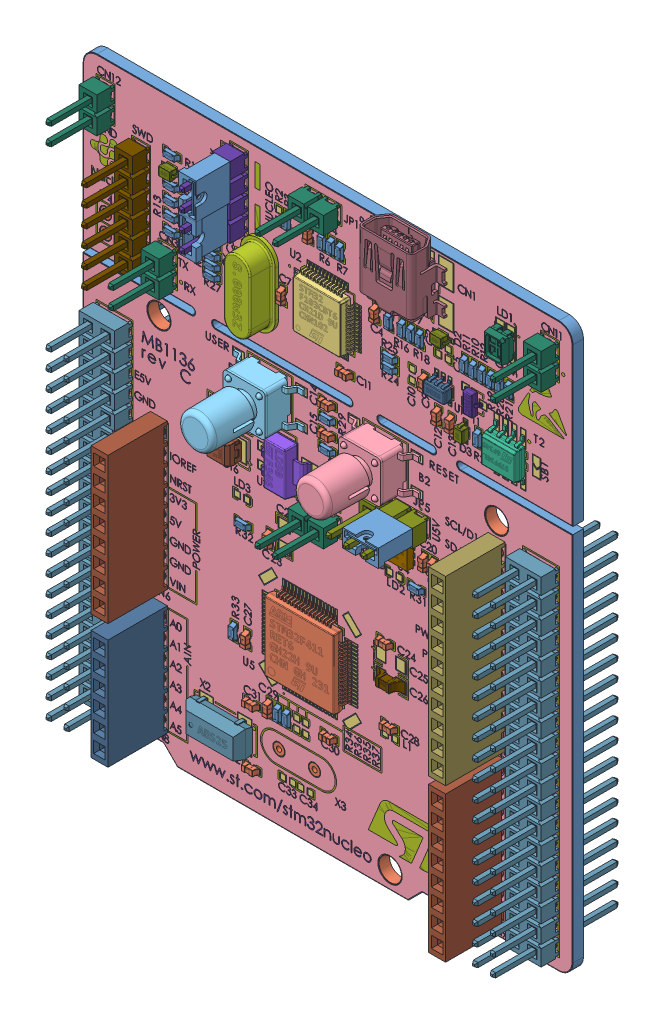
SolidWorks assembly NUCLEO-F4, configuration По умолчанию. Lengths in mm.
Overall size (70 83.97 20.27).
102 component instances, 38 part files, 0 mates.
Components (placement in the parent):
- NUCLEO-F411RE_PCB_VarsayВЌlan-1: NUCLEO-F411RE_PCB_VarsayВЌlan [По умолчанию] at origin size (70 82.5 1.5)
- NUCLEO-F411RE_PCB_HOLEs_VarsayВЌlan-1: NUCLEO-F411RE_PCB_HOLEs_VarsayВЌlan [По умолчанию] at origin size (65.28 79.87 1.57)
- NUCLEO-F411RE_PCB_TOP_Pads_VarsayВЌlan-1: NUCLEO-F411RE_PCB_TOP_Pads_VarsayВЌlan [По умолчанию] at origin size (59.94 77.1 0.04)
- NUCLEO-F411RE_PCB_TOP_Solder_VarsayВЌlan-1: NUCLEO-F411RE_PCB_TOP_Solder_VarsayВЌlan [По умолчанию] at origin size (69.8 82.3 0.05)
- NUCLEO-F411RE_PCB_BOTTOM_Pads_VarsayВЌlan-1: NUCLEO-F411RE_PCB_BOTTOM_Pads_VarsayВЌlan [По умолчанию] at origin size (31.1 70.87 0.04)
- NUCLEO-F411RE_PCB_BOTTOM_Solder_VarsayВЌlan-1: NUCLEO-F411RE_PCB_BOTTOM_Solder_VarsayВЌlan [По умолчанию] at origin size (69.8 82.3 0.04)
- NUCLEO-F411RE_PCB_TOP_Overlay_VarsayВЌlan-1: NUCLEO-F411RE_PCB_TOP_Overlay_VarsayВЌlan [По умолчанию] at origin size (68.11 77.69 0.03)
- NUCLEO-F411RE_PCB_TOP_Designators_VarsayВЌlan-1: NUCLEO-F411RE_PCB_TOP_Designators_VarsayВЌlan [По умолчанию] at origin size (66.31 79.66 0.03)
- NUCLEO-F411RE_PCB_BOTTOM_Overlay_VarsayВЌlan-1: NUCLEO-F411RE_PCB_BOTTOM_Overlay_VarsayВЌlan [По умолчанию] at origin size (40.14 80.79 0.03)
- SAMTEC_SSQ-106-01-G-S_for_NUCLEO_VarsayВЌlan-1: SAMTEC_SSQ-106-01-G-S_for_NUCLEO_VarsayВЌlan [По умолчанию] at (-33.02 8.89 0.785) x (0 1 0) z (1 0 0) size (15.75 11.15 2.41)
- SAMTEC_SSQ-108-01-G-S_for_NUCLEO_VarsayВЌlan-1: SAMTEC_SSQ-108-01-G-S_for_NUCLEO_VarsayВЌlan [По умолчанию] at (-33.02 29.21 0.785) x (0 1 0) z (1 0 0) size (20.83 11.15 2.41)
- SAMTEC_SSQ-110-01-G-S_for_NUCLEO_VarsayВЌlan-1: SAMTEC_SSQ-110-01-G-S_for_NUCLEO_VarsayВЌlan [По умолчанию] at (15.24 35.814 0.785) x (0 1 0) z (1 0 0) size (25.91 11.15 2.41)
- MOLEX_0678038020_for_NUCLEO-1: MOLEX_0678038020_for_NUCLEO [По умолчанию] at (3.1721 75.2975 0.785) x (-1 0 0) z (0 1 0) size (9.9 4.95 9)
- SAMTEC_TSW-119-07-T-D_for_NUCLEO_VarsayВЌlan-1: SAMTEC_TSW-119-07-T-D_for_NUCLEO_VarsayВЌlan [По умолчанию] at (-39.37 25.4 0.785) x (0 -1 0) z (-1 0 0) size (48.26 17.95 5.08)
- SAMTEC_TSW-102-07-T-S_for_NUCLEO_VarsayВЌlan-1: SAMTEC_TSW-102-07-T-S_for_NUCLEO_VarsayВЌlan [По умолчанию] at (-40.64 74.93 0.785) x (0 1 0) z (1 0 0) size (5.08 10.92 2.54)
- SAMTEC_TSW-103-07-T-S_for_NUCLEO_VarsayВЌlan-1: SAMTEC_TSW-103-07-T-S_for_NUCLEO_VarsayВЌlan [По умолчанию] at (1.905 45.085 0.785) x (1 0 0) z (0 -1 0) size (7.62 10.92 2.54)
- SAMTEC_TSW-104-07-T-S_for_NUCLEO_VarsayВЌlan-1: SAMTEC_TSW-104-07-T-S_for_NUCLEO_VarsayВЌlan [По умолчанию] at (-21.59 73.66 0.785) x (0 1 0) z (1 0 0) size (10.16 10.92 2.54)
- SAMTEC_TSW-106-07-T-S_for_NUCLEO_VarsayВЌlan-1: SAMTEC_TSW-106-07-T-S_for_NUCLEO_VarsayВЌlan [По умолчанию] at (-35.56 64.77 0.785) x (0 1 0) z (1 0 0) size (15.24 10.92 2.54)
- MOLEX_90059-0007-1: MOLEX_90059-0007 [По умолчанию] at (-21.59 76.2 5.75) x (0 1 0) z (1 0 0) size (5.1 4.85 2.54)
- ST_STM32F411RET6_VarsayВЌlan-1: ST_STM32F411RET6_VarsayВЌlan [По умолчанию] at (-11.4265 21.5935 0.785) x (-1 0 0) z (0 0 -1) size (12 12 1.61)
- ST_STM32F103CBT6_VarsayВЌlan-1: ST_STM32F103CBT6_VarsayВЌlan [По умолчанию] at (-8.89 64.77 0.785) x (1 0 0) z (0 -1 0) size (9 1.61 9)
- ESWITCH_TL3301SPF160QGBLK_VarsayВЌlan-1: ESWITCH_TL3301SPF160QGBLK_VarsayВЌlan [По умолчанию] at (-0.635 50.8 0.785) x (0 -1 0) z (-1 0 0) size (6.01 10.7 10)
- ESWITCH_TL3301SPF160QGBLU_VarsayВЌlan-1: ESWITCH_TL3301SPF160QGBLU_VarsayВЌlan [По умолчанию] at (-17.145 50.8 0.785) x (0 1 0) z (1 0 0) size (6.01 10.7 10)
- ST_STS7PF30L_VarsayВЌlan-1: ST_STS7PF30L_VarsayВЌlan [По умолчанию] at (17.145 60.325 0.785) x (-1 0 0) z (0 1 0) size (4.91 1.76 6)
- ABRACON_ABL-8-1: ABRACON_ABL-8 [По умолчанию] at (-18.41 63.4908 0.785) x (0 -1 0) z (-1 0 0) size (11.5 5.59 5)
- ST_LD1117S50TR_VarsayВЌlan-1: ST_LD1117S50TR_VarsayВЌlan [По умолчанию] at (-14.6685 43.18 0.785) x (0 -1 0) z (-1 0 0) size (6.51 1.91 7)
- ST_LD39050PU33R_VarsayВЌlan-1: ST_LD39050PU33R_VarsayВЌlan [По умолчанию] at (1.905 40.64 0.785) x (0 1 0) z (1 0 0) size (3.01 1.01 3.01)
- ST_LD3985M33R_VarsayВЌlan-1: ST_LD3985M33R_VarsayВЌlan [По умолчанию] at (7.62 63.5 0.785) x (1 0 0) z (0 -1 0) size (2.96 1.46 2.8)
- KEMET_T491B106K025AT_VarsayВЌlan-1: KEMET_T491B106K025AT_VarsayВЌlan [По умолчанию] at (-22.86 41.275 0.785) x (0 -1 0) z (-1 0 0) size (2.81 1.91 3.5)
- ST_STPS2L30A_VarsayВЌlan-1: ST_STPS2L30A_VarsayВЌlan [По умолчанию] at (-22.86 45.085 0.785) x (0 1 0) z (1 0 0) size (2.59 2.31 5.07)
- KEMET_T491A106K006AT7280_VarsayВЌlan-1: KEMET_T491A106K006AT7280_VarsayВЌlan [По умолчанию] at (-8.255 43.053 0.785) x (1 0 0) z (0 -1 0) size (1.61 1.61 3.2)
- ABRACON_ABS25-32-1: ABRACON_ABS25-32 [По умолчанию] at (-23.495 6.35 0.785) x (1 0 0) z (0 -1 0) size (8 2.67 4)
- LUMEX_SML-LX2835IGC-TR-1: LUMEX_SML-LX2835IGC-TR [По умолчанию] at (16.51 73.66 0.785) x (1 0 0) z (0 -1 0) size (2.7 1.8 3.5)
- ST_BAT60JFILM_VarsayВЌlan-1: ST_BAT60JFILM_VarsayВЌlan [По умолчанию] at (-31.115 71.12 0.785) x (0 -1 0) z (-1 0 0) size (1.29 1.18 2.5)
- NXP_BC847B,215-1: NXP_BC847B,215 [По умолчанию] at (12.065 64.135 0.785) x (0 -1 0) z (-1 0 0) size (2.9 1.11 2.43)
- YAGEO_CC0805KKX7R7BB225-1: YAGEO_CC0805KKX7R7BB225 [По умолчанию] at (0.127 23.495 0.785) x (0 -1 0) z (-1 0 0) size (1.59 1.29 4.06)
- YAGEO_RC0603JR-070RL-1: YAGEO_RC0603JR-070RL [По умолчанию] at (17.145 67.945 0.785) x (1 0 0) z (0 -1 0) size (0.8 0.55 2.16)
- YAGEO_CC0603KRX7R7BB104-1: YAGEO_CC0603KRX7R7BB104 [По умолчанию] at (-11.43 73.025 0.785) x (1 0 0) z (0 -1 0) size (0.8 0.8 2.16)
- SAMTEC_SSQ-108-01-G-S_for_NUCLEO_VarsayВЌlan-2: SAMTEC_SSQ-108-01-G-S_for_NUCLEO_VarsayВЌlan [По умолчанию] at (15.24 11.43 0.785) x (0 1 0) z (1 0 0) size (20.83 11.15 2.41)
- SAMTEC_TSW-119-07-T-D_for_NUCLEO_VarsayВЌlan-2: SAMTEC_TSW-119-07-T-D_for_NUCLEO_VarsayВЌlan [По умолчанию] at (21.59 25.4 0.785) x (0 -1 0) z (-1 0 0) size (48.26 17.95 5.08)
- SAMTEC_TSW-102-07-T-S_for_NUCLEO_VarsayВЌlan-2: SAMTEC_TSW-102-07-T-S_for_NUCLEO_VarsayВЌlan [По умолчанию] at (-31.75 59.055 0.785) x (0 -1 0) z (-1 0 0) size (5.08 10.92 2.54)
- SAMTEC_TSW-102-07-T-S_for_NUCLEO_VarsayВЌlan-3: SAMTEC_TSW-102-07-T-S_for_NUCLEO_VarsayВЌlan [По умолчанию] at (-9.525 77.47 0.785) x (1 0 0) z (0 -1 0) size (5.08 10.92 2.54)
- SAMTEC_TSW-102-07-T-S_for_NUCLEO_VarsayВЌlan-4: SAMTEC_TSW-102-07-T-S_for_NUCLEO_VarsayВЌlan [По умолчанию] at (-9.525 38.735 0.785) x (1 0 0) z (0 -1 0) size (5.08 10.92 2.54)
- SAMTEC_TSW-102-07-T-S_for_NUCLEO_VarsayВЌlan-5: SAMTEC_TSW-102-07-T-S_for_NUCLEO_VarsayВЌlan [По умолчанию] at (22.86 74.93 0.785) x (0 -1 0) z (-1 0 0) size (5.08 10.92 2.54)
- MOLEX_90059-0007-2: MOLEX_90059-0007 [По умолчанию] at (-21.59 71.12 5.75) x (0 -1 0) z (-1 0 0) size (5.1 4.85 2.54)
- MOLEX_90059-0007-3: MOLEX_90059-0007 [По умолчанию] at (3.175 45.085 5.75) x (-1 0 0) z (0 1 0) size (5.1 4.85 2.54)
- ST_BAT60JFILM_VarsayВЌlan-2: ST_BAT60JFILM_VarsayВЌlan [По умолчанию] at (7.62 69.85 0.785) x (0 -1 0) z (-1 0 0) size (1.29 1.18 2.5)
- ST_BAT60JFILM_VarsayВЌlan-3: ST_BAT60JFILM_VarsayВЌlan [По умолчанию] at (10.795 59.69 0.785) x (1 0 0) z (0 -1 0) size (1.29 1.18 2.5)
- YAGEO_RC0603JR-070RL-2: YAGEO_RC0603JR-070RL [По умолчанию] at (15.875 67.945 0.785) x (1 0 0) z (0 -1 0) size (0.8 0.55 2.16)
- YAGEO_RC0603JR-070RL-3: YAGEO_RC0603JR-070RL [По умолчанию] at (14.605 67.945 0.785) x (1 0 0) z (0 -1 0) size (0.8 0.55 2.16)
- YAGEO_RC0603JR-070RL-4: YAGEO_RC0603JR-070RL [По умолчанию] at (13.335 67.945 0.785) x (1 0 0) z (0 -1 0) size (0.8 0.55 2.16)
- YAGEO_RC0603JR-070RL-5: YAGEO_RC0603JR-070RL [По умолчанию] at (12.065 67.945 0.785) x (1 0 0) z (0 -1 0) size (0.8 0.55 2.16)
- YAGEO_RC0603JR-070RL-6: YAGEO_RC0603JR-070RL [По умолчанию] at (10.795 67.945 0.785) x (1 0 0) z (0 -1 0) size (0.8 0.55 2.16)
- YAGEO_RC0603JR-070RL-7: YAGEO_RC0603JR-070RL [По умолчанию] at (12.7 59.7535 0.785) x (1 0 0) z (0 -1 0) size (0.8 0.55 2.16)
- YAGEO_RC0603JR-070RL-8: YAGEO_RC0603JR-070RL [По умолчанию] at (4.445 67.945 0.785) x (1 0 0) z (0 -1 0) size (0.8 0.55 2.16)
- YAGEO_RC0603JR-070RL-9: YAGEO_RC0603JR-070RL [По умолчанию] at (3.175 67.945 0.785) x (1 0 0) z (0 -1 0) size (0.8 0.55 2.16)
- YAGEO_RC0603JR-070RL-10: YAGEO_RC0603JR-070RL [По умолчанию] at (1.905 67.945 0.785) x (1 0 0) z (0 -1 0) size (0.8 0.55 2.16)
- YAGEO_RC0603JR-070RL-11: YAGEO_RC0603JR-070RL [По умолчанию] at (0 67.945 0.785) x (1 0 0) z (0 -1 0) size (0.8 0.55 2.16)
- YAGEO_RC0603JR-070RL-12: YAGEO_RC0603JR-070RL [По умолчанию] at (-6.985 73.025 0.785) x (1 0 0) z (0 -1 0) size (0.8 0.55 2.16)
- YAGEO_RC0603JR-070RL-13: YAGEO_RC0603JR-070RL [По умолчанию] at (-8.255 73.025 0.785) x (1 0 0) z (0 -1 0) size (0.8 0.55 2.16)
- YAGEO_RC0603JR-070RL-14: YAGEO_RC0603JR-070RL [По умолчанию] at (-9.525 73.025 0.785) x (1 0 0) z (0 -1 0) size (0.8 0.55 2.16)
- YAGEO_RC0603JR-070RL-15: YAGEO_RC0603JR-070RL [По умолчанию] at (-14.605 73.025 0.785) x (1 0 0) z (0 -1 0) size (0.8 0.55 2.16)
- YAGEO_RC0603JR-070RL-16: YAGEO_RC0603JR-070RL [По умолчанию] at (-31.115 73.025 0.785) x (0 -1 0) z (-1 0 0) size (0.8 0.55 2.16)
- YAGEO_RC0603JR-070RL-17: YAGEO_RC0603JR-070RL [По умолчанию] at (-31.115 69.215 0.785) x (0 -1 0) z (-1 0 0) size (0.8 0.55 2.16)
- YAGEO_RC0603JR-070RL-18: YAGEO_RC0603JR-070RL [По умолчанию] at (-31.115 67.31 0.785) x (0 -1 0) z (-1 0 0) size (0.8 0.55 2.16)
- YAGEO_RC0603JR-070RL-19: YAGEO_RC0603JR-070RL [По умолчанию] at (-31.115 65.405 0.785) x (0 -1 0) z (-1 0 0) size (0.8 0.55 2.16)
- YAGEO_RC0603JR-070RL-20: YAGEO_RC0603JR-070RL [По умолчанию] at (-31.115 63.5 0.785) x (0 -1 0) z (-1 0 0) size (0.8 0.55 2.16)
- YAGEO_RC0603JR-070RL-21: YAGEO_RC0603JR-070RL [По умолчанию] at (-25.4 64.77 0.785) x (0 -1 0) z (-1 0 0) size (0.8 0.55 2.16)
- YAGEO_RC0603JR-070RL-22: YAGEO_RC0603JR-070RL [По умолчанию] at (-25.4 63.5 0.785) x (0 -1 0) z (-1 0 0) size (0.8 0.55 2.16)
- YAGEO_RC0603JR-070RL-23: YAGEO_RC0603JR-070RL [По умолчанию] at (-25.4 62.23 0.785) x (0 -1 0) z (-1 0 0) size (0.8 0.55 2.16)
- YAGEO_RC0603JR-070RL-24: YAGEO_RC0603JR-070RL [По умолчанию] at (-25.4 60.96 0.785) x (0 -1 0) z (-1 0 0) size (0.8 0.55 2.16)
- YAGEO_RC0603JR-070RL-25: YAGEO_RC0603JR-070RL [По умолчанию] at (-15.875 11.43 0.785) x (1 0 0) z (0 -1 0) size (0.8 0.55 2.16)
- YAGEO_RC0603JR-070RL-26: YAGEO_RC0603JR-070RL [По умолчанию] at (-14.605 11.43 0.785) x (1 0 0) z (0 -1 0) size (0.8 0.55 2.16)
- YAGEO_RC0603JR-070RL-27: YAGEO_RC0603JR-070RL [По умолчанию] at (-22.225 18.415 0.785) x (1 0 0) z (0 -1 0) size (0.8 0.55 2.16)
- YAGEO_RC0603JR-070RL-28: YAGEO_RC0603JR-070RL [По умолчанию] at (-20.955 32.385 0.785) x (0 -1 0) z (-1 0 0) size (0.8 0.55 2.16)
- YAGEO_RC0603JR-070RL-29: YAGEO_RC0603JR-070RL [По умолчанию] at (-8.89 51.435 0.785) x (0 -1 0) z (-1 0 0) size (0.8 0.55 2.16)
- YAGEO_RC0603JR-070RL-30: YAGEO_RC0603JR-070RL [По умолчанию] at (-8.89 47.625 0.785) x (0 -1 0) z (-1 0 0) size (0.8 0.55 2.16)
- YAGEO_RC0603JR-070RL-31: YAGEO_RC0603JR-070RL [По умолчанию] at (3.81 36.83 0.785) x (0 -1 0) z (-1 0 0) size (0.8 0.55 2.16)
- YAGEO_RC0603JR-070RL-32: YAGEO_RC0603JR-070RL [По умолчанию] at (0 63.5 0.785) x (0 -1 0) z (-1 0 0) size (0.8 0.55 2.16)
- YAGEO_RC0603JR-070RL-33: YAGEO_RC0603JR-070RL [По умолчанию] at (0 62.23 0.785) x (0 -1 0) z (-1 0 0) size (0.8 0.55 2.16)
- YAGEO_CC0603KRX7R7BB104-2: YAGEO_CC0603KRX7R7BB104 [По умолчанию] at (-1.905 67.945 0.785) x (1 0 0) z (0 -1 0) size (0.8 0.8 2.16)
- YAGEO_CC0603KRX7R7BB104-3: YAGEO_CC0603KRX7R7BB104 [По умолчанию] at (5.08 62.865 0.785) x (1 0 0) z (0 -1 0) size (0.8 0.8 2.16)
- YAGEO_CC0603KRX7R7BB104-4: YAGEO_CC0603KRX7R7BB104 [По умолчанию] at (6.985 59.69 0.785) x (1 0 0) z (0 -1 0) size (0.8 0.8 2.16)
- YAGEO_CC0603KRX7R7BB104-5: YAGEO_CC0603KRX7R7BB104 [По умолчанию] at (8.89 59.69 0.785) x (1 0 0) z (0 -1 0) size (0.8 0.8 2.16)
- YAGEO_CC0603KRX7R7BB104-6: YAGEO_CC0603KRX7R7BB104 [По умолчанию] at (-21.59 62.23 0.785) x (1 0 0) z (0 -1 0) size (0.8 0.8 2.16)
- YAGEO_CC0603KRX7R7BB104-7: YAGEO_CC0603KRX7R7BB104 [По умолчанию] at (-21.59 64.77 0.785) x (1 0 0) z (0 -1 0) size (0.8 0.8 2.16)
- YAGEO_CC0603KRX7R7BB104-8: YAGEO_CC0603KRX7R7BB104 [По умолчанию] at (-15.24 63.5 0.785) x (1 0 0) z (0 -1 0) size (0.8 0.8 2.16)
- YAGEO_CC0603KRX7R7BB104-9: YAGEO_CC0603KRX7R7BB104 [По умолчанию] at (-6.35 58.42 0.785) x (0 -1 0) z (-1 0 0) size (0.8 0.8 2.16)
- YAGEO_CC0603KRX7R7BB104-10: YAGEO_CC0603KRX7R7BB104 [По умолчанию] at (-8.89 53.34 0.785) x (0 -1 0) z (-1 0 0) size (0.8 0.8 2.16)
- YAGEO_CC0603KRX7R7BB104-11: YAGEO_CC0603KRX7R7BB104 [По умолчанию] at (-8.89 49.53 0.785) x (0 -1 0) z (-1 0 0) size (0.8 0.8 2.16)
- YAGEO_CC0603KRX7R7BB104-12: YAGEO_CC0603KRX7R7BB104 [По умолчанию] at (-2.54 40.64 0.785) x (1 0 0) z (0 -1 0) size (0.8 0.8 2.16)
- YAGEO_CC0603KRX7R7BB104-13: YAGEO_CC0603KRX7R7BB104 [По умолчанию] at (-1.27 40.64 0.785) x (1 0 0) z (0 -1 0) size (0.8 0.8 2.16)
- YAGEO_CC0603KRX7R7BB104-14: YAGEO_CC0603KRX7R7BB104 [По умолчанию] at (5.08 40.64 0.785) x (1 0 0) z (0 -1 0) size (0.8 0.8 2.16)
- YAGEO_CC0603KRX7R7BB104-15: YAGEO_CC0603KRX7R7BB104 [По умолчанию] at (6.35 40.64 0.785) x (1 0 0) z (0 -1 0) size (0.8 0.8 2.16)
- YAGEO_CC0603KRX7R7BB104-16: YAGEO_CC0603KRX7R7BB104 [По умолчанию] at (-0.6033 27.94 0.785) x (0 -1 0) z (-1 0 0) size (0.8 0.8 2.16)
- YAGEO_CC0603KRX7R7BB104-17: YAGEO_CC0603KRX7R7BB104 [По умолчанию] at (-17.145 32.385 0.785) x (1 0 0) z (0 -1 0) size (0.8 0.8 2.16)
- YAGEO_CC0603KRX7R7BB104-18: YAGEO_CC0603KRX7R7BB104 [По умолчанию] at (-20.32 18.415 0.785) x (1 0 0) z (0 -1 0) size (0.8 0.8 2.16)
- YAGEO_CC0603KRX7R7BB104-19: YAGEO_CC0603KRX7R7BB104 [По умолчанию] at (-17.145 11.43 0.785) x (1 0 0) z (0 -1 0) size (0.8 0.8 2.16)
- YAGEO_CC0603KRX7R7BB104-20: YAGEO_CC0603KRX7R7BB104 [По умолчанию] at (0 17.78 0.785) x (0 -1 0) z (-1 0 0) size (0.8 0.8 2.16)
- YAGEO_CC0603KRX7R7BB104-21: YAGEO_CC0603KRX7R7BB104 [По умолчанию] at (-8.636 12.192 0.785) x (0 -1 0) z (-1 0 0) size (0.8 0.8 2.16)
- YAGEO_CC0603KRX7R7BB104-22: YAGEO_CC0603KRX7R7BB104 [По умолчанию] at (-19.685 2.794 0.785) x (0 -1 0) z (-1 0 0) size (0.8 0.8 2.16)
- YAGEO_CC0603KRX7R7BB104-23: YAGEO_CC0603KRX7R7BB104 [По умолчанию] at (-19.685 10.795 0.785) x (0 -1 0) z (-1 0 0) size (0.8 0.8 2.16)
